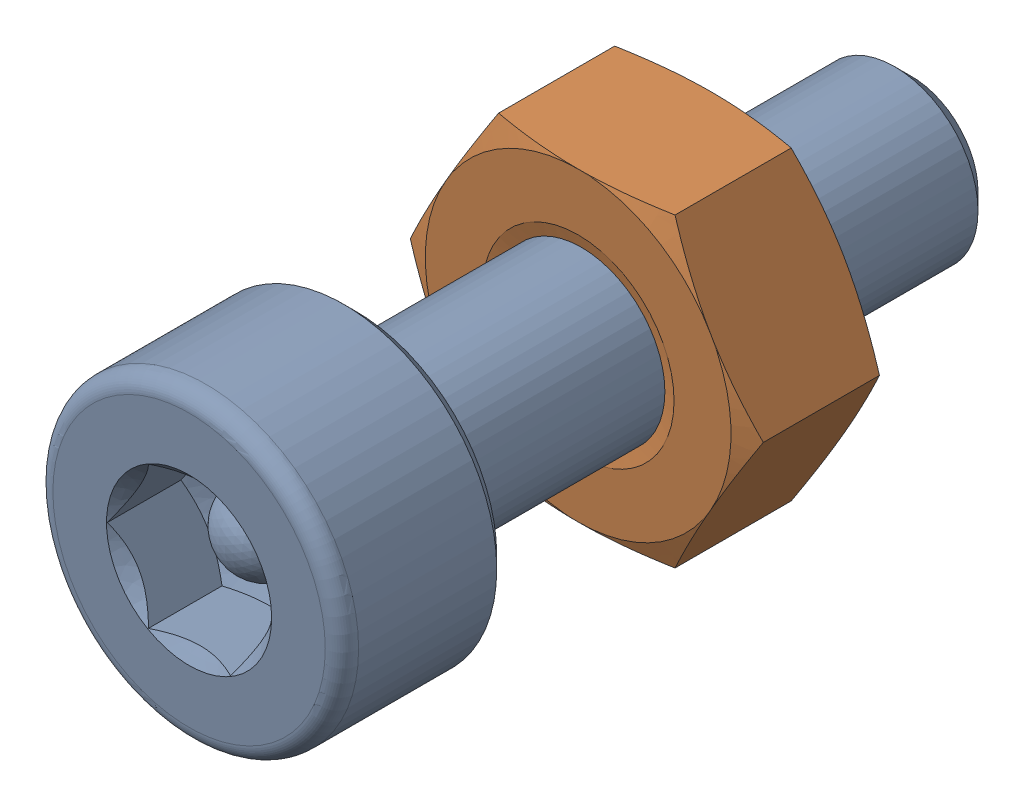
SolidWorks assembly Screw and Nut M3x010_015-1, configuration Varsayılan. Lengths in mm.
Overall size (6.35 5.5 13.14).
2 component instances, 2 part files, 0 mates.
Components (placement in the parent):
- M3x10-Screw014-1-1: M3x10-Screw014-1 [Varsayılan] at origin size (5.5 5.5 13.14)
- M3-Nut046-1-1: M3-Nut046-1 [Varsayılan] at (0 0 -4) x (-1 0 0) z (0 0 -1) size (6.35 5.5 2.4)
